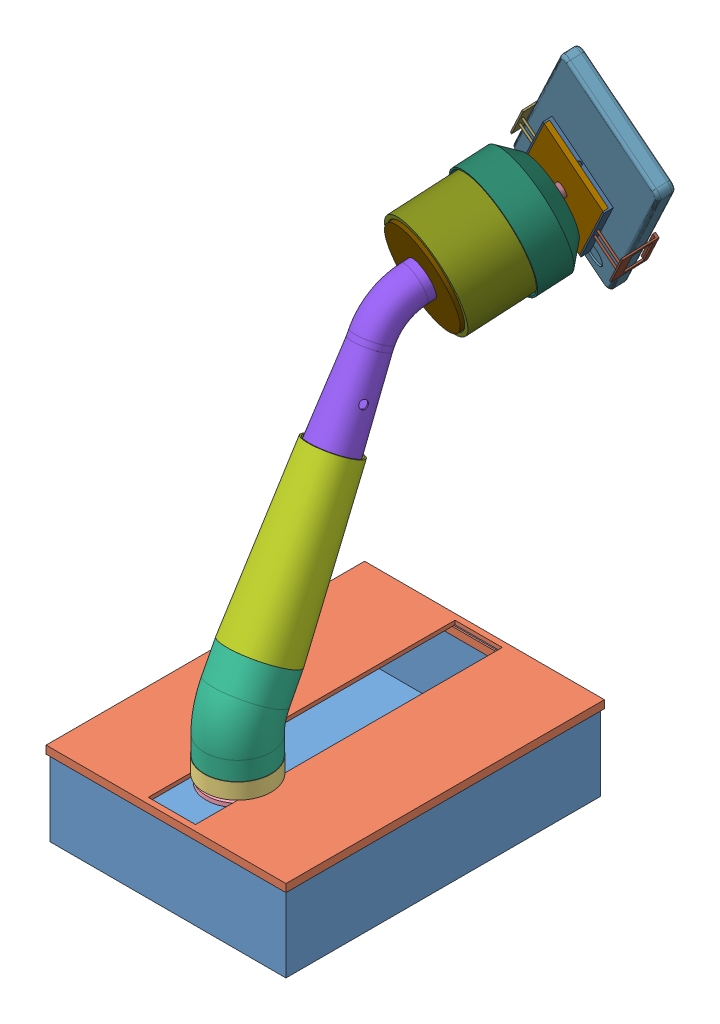
SolidWorks assembly K.K Project substitute, configuration Default. Lengths in mm.
Overall size (194.13 400.03 286.69).
24 component instances, 18 part files, 12 mates.
Components (placement in the parent):
- Base-1: Base [Default] at (6.3316 -25.6599 17.6861) size (152.5 52.5 202.5)
  - BS 1-1: BS 1 [Default] at (90.3644 102.493 247.3524) size (150 50 200)
  - aaaa-1: aaaa [Default] at (89.6144 129.993 146.6024) size (152.5 7.5 202.5)
- Clamping-1: Clamping [Default] at (1.0301 -25.6599 132.4327) x (0.998276 0 -0.058689) z (0.058689 0 0.998276) size (58.11 35 58.11)
  - BS 6-1: BS 6 [Default] at (89.6144 129.993 92.9643) x (0.86441 0 0.502787) z (-0.502787 0 0.86441) size (42.5 10 42.5)
  - BS 7-1: BS 7 [Default] at (89.6144 124.993 92.9643) x (0.837169 0 -0.546944) z (0.546944 0 0.837169) size (40 2.5 40)
  - BS 8-1: BS 8 [Default] at (89.6144 124.993 92.9643) x (0.67559 0 0.737277) z (0 -1 0) size (15 15 35)
- Trunck-1: Trunck [Default] at (206.8562 -27.7179 220.8642) x (-0.342448 0 0.939537) z (-0.939537 0 -0.342448) size (152.43 235.58 90.99)
  - BS 3. I-1: BS 3. I [Default] at (37.1478 134.551 104.5079) x (-0.914567 0 0.404435) z (-0.404435 0 -0.914567) size (54.19 66.48 42)
  - BS 3. II-1: BS 3. II [Default] at (23.4293 190.5318 110.5744) x (0.742307 0.496917 -0.449504) z (0.489767 0.055443 0.870089) size (42 100 42)
  - BS 5-2: BS 5 [Default] at (0.5874 233.7909 120.6755) x (0.887939 0.457283 0.049555) z (0.049555 -0.202218 0.978086) size (41.61 144.11 35)
- Frame-1: Frame [Default] at (132.8589 345.8311 481.7373) x (0.996584 -0.08179 -0.011454) z (0.070557 0.915262 -0.396632) size (93.24 66.21 78.95)
  - bouchon arriere-1: bouchon arriere [Default] at (-16.8253 388.9814 206.1696) x (0.849584 0.176426 -0.497072) z (0.221148 0.73642 0.639359) size (48 80 3.8)
  - bRAS 2-1: bRAS 2 [Default] at (155.286 158.0911 420.3999) x (0.849584 0.176426 -0.497072) z (0.221148 0.73642 0.639359) size (50 80 5)
  - encadrement bras 2 partie gauche-1: encadrement bras 2 partie gauche [Default] at (22.3931 427.2278 148.5517) x (-0.849584 -0.176426 0.497072) z (-0.478853 0.653116 -0.586634) size (25 20 40)
  - encadrement bras 2 partie droite-1: encadrement bras 2 partie droite [Default] at (-45.5736 413.1137 188.3175) x (-0.849584 -0.176426 0.497072) z (-0.478853 0.653116 -0.586634) size (25 20 40)
  - Assem2^Frame-1: Assem2^Frame [Default] at origin (virtual)
  - émant collé sur le telephone-2: émant collé sur le telephone [Default] at (-15.4789 419.7085 171.0941) x (0.970167 -0.099343 -0.221148) z (0.221148 0.73642 0.639359) size (20 20 20.6)
- Cobaye-1: Cobaye [Default] at (135.1982 363.8966 26.839) x (-0.804037 0.594033 -0.025482) z (0.546643 0.755393 0.361337) size (80 10 170)
- Arm substitute assembly-2: Arm substitute assembly [Default] at (87.1616 334.084 12.8137) x (0.788932 -0.61448 -0.000673) z (-0.22432 -0.289024 0.930669) size (82.61 82.61 73.14)
  - Arm substitute 1-1: Arm substitute 1 [Default] at (16.3915 22.8204 16.2487) size (69 69 30)
  - Arm substitute 2-2: Arm substitute 2 [Default] at (16.3915 22.8204 83.2487) x (0.10756 -0.994199 0) z (0 0 -1) size (65 65 50)
  - partie émant-1: partie émant [Default] at (5.5446 10.721 28.1343) x (0.6675 0.744577 0.00704) z (-0.744455 0.667524 -0.014089) size (32.5 31.14 32.5)
  - cover of arm substitute 2-1: cover of arm substitute 2 [Default] at (16.3915 22.8204 85.3638) x (-0.79943 0.60076 0) z (0 0 -1) size (59 59 5)
Mates (geometry in assembly coordinates):
- Coincident1: coincident anti-aligned: plane of Base-1/aaaa-1 through (95.946 104.3331 164.2885) normal (0 1 0); plane of Clamping-1/BS 6-1 through (95.946 104.3331 219.9774) normal (0 -1 0)
- Tangent1: tangent anti-aligned: plane of Base-1/aaaa-1 through (115.946 98.8331 71.5385) normal (-1 0 0); cylinder of Clamping-1/BS 7-1 through (95.946 101.8331 219.9774) axis (0 -1 0) radius 20
- Concentric1: concentric aligned: cylinder of Clamping-1/BS 6-1 through (95.946 106.8331 219.9774) axis (0 1 0) radius 20.75; cylinder of Trunck-1/BS 3. I-1 through (95.946 106.8331 219.9774) axis (0 1 0) radius 21
- Concentric2: concentric aligned: circle of Clamping-1/BS 6-1; circle of Trunck-1/BS 3. I-1
- Coincident2: coincident anti-aligned: plane of Clamping-1/BS 6-1 through (95.946 106.8331 219.9774) normal (0 1 0); plane of Trunck-1/BS 3. I-1 through (95.946 106.8331 219.9774) normal (0 -1 0)
- Coincident6: coincident anti-aligned: plane of Frame-1/bRAS 2-1 through (310.4907 655.5444 168.1019) normal (0.233895 0.276599 -0.932087); plane of Cobaye-1 through (132.8593 361.1306 36.1599) normal (-0.233895 -0.276599 0.932087)
- Coincident7: coincident anti-aligned: plane of Frame-1/encadrement bras 2 partie droite-1 through (82.1918 359.552 28.3414) normal (0.804037 -0.594033 0.025482); plane of Cobaye-1 through (54.2332 320.6835 4.427) normal (-0.804037 0.594033 -0.025482)
- Coincident8: coincident anti-aligned: plane of Frame-1/encadrement bras 2 partie gauche-1 through (146.5148 312.0293 30.38) normal (-0.804037 0.594033 -0.025482); plane of Cobaye-1 through (118.5561 273.1609 6.4655) normal (0.804037 -0.594033 0.025482)
- Coincident9: coincident anti-aligned: plane of Trunck-1/BS 5-2 through (94.4481 316.6696 98.7358) normal (0.22432 0.289024 -0.930669); plane of Arm substitute assembly-2/cover of arm substitute 2-1 through (94.4481 316.6696 98.7358) normal (-0.22432 -0.289024 0.930669)
- Concentric3: concentric anti-aligned: cylinder of Trunck-1/BS 5-2 through (92.9852 314.7848 104.8051) axis (0.22432 0.289024 -0.930669) radius 11; cylinder of Arm substitute assembly-2/cover of arm substitute 2-1 through (94.4481 316.6696 98.7358) axis (-0.22432 -0.289024 0.930669) radius 10.1
- Concentric4: concentric aligned: cylinder of Frame-1/émant collé sur le telephone-2 through (106.8116 332.5992 47.4419) axis (0.233895 0.276599 -0.932087) radius 4; cone of Arm substitute assembly-2/partie émant-1 through (110.6123 337.094 32.2955) axis (0.233895 0.276599 -0.932087)
- Coincident11: coincident anti-aligned: plane of Frame-1/émant collé sur le telephone-2 through (106.8116 332.5992 47.4419) normal (-0.233895 -0.276599 0.932087); plane of Arm substitute assembly-2/partie émant-1 through (106.8116 332.5992 47.4419) normal (0.233895 0.276599 -0.932087)
